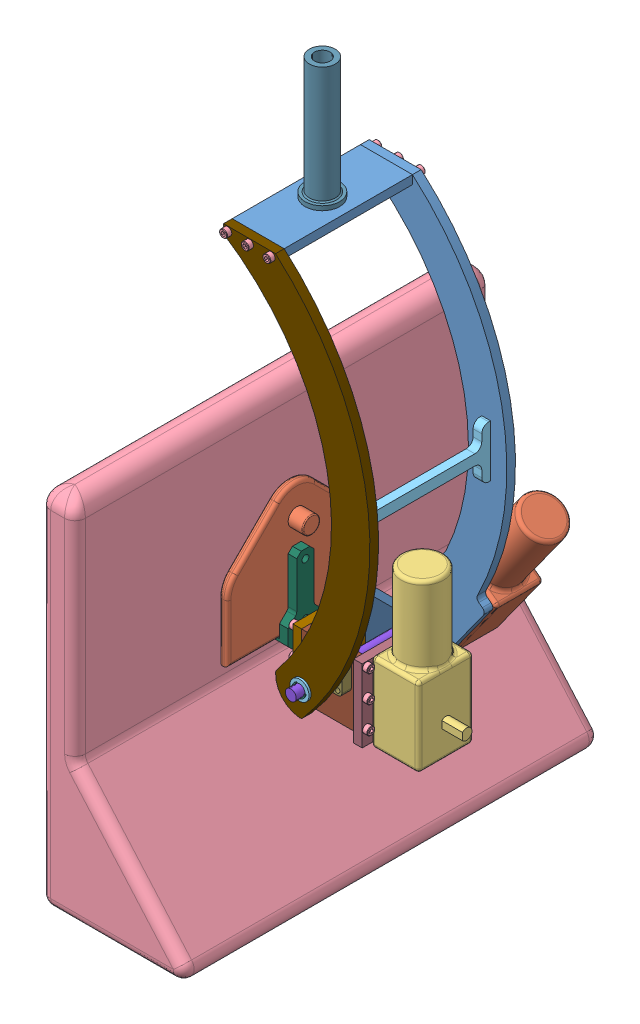
SolidWorks assembly Wrist Assembly, configuration Zero position. Lengths in mm.
Overall size (162.26 489.02 304.8).
43 component instances, 23 part files, 72 mates.
Components (placement in the parent):
- Wrist Gap (1)-1: Wrist Gap (1) [Default] at (19.05 641.296 -56.0544) x (0 0 -1) z (0 1 0)
- Screen Holder-1: Screen Holder [Default] at (-5.9436 364.1185 -55.987) x (0 0 -1) z (1 0 0)
- 8mm Bottom Shaft-1: 8mm Bottom Shaft [Default] at (59.7789 359.356 -56.0544) x (0 0 -1) z (-1 0 0)
- Tobii Screen-1: Tobii Screen [Default] at (-35.1536 247.5282 -208.387)
- 8mmBushing__5448T200_MULTIPURPOSE FLANGED SLEEVE BEARING-1: 8mmBushing__5448T200_MULTIPURPOSE FLANGED SLEEVE BEARING [5448T2] at (57.15 380.946 -1.2144) x (0.886816 0.462123 0) z (-0.462123 0.886816 0)
- 98808A340_LOW CLEARANCE EXTERNAL RETAINING RING-1: 98808A340_LOW CLEARANCE EXTERNAL RETAINING RING [98808A340] at (57.15 380.946 -0.8969) x (0 0 -1) z (0.826634 -0.56274 0)
- 5395T211_SET SCREW RIGID SHAFT COUPLING (1)-3: 5395T211_SET SCREW RIGID SHAFT COUPLING (1) [5395T211] at (57.15 380.946 -96.1006) x (0.038678 0.999252 0) z (0 0 1)
- 5395T211_SET SCREW RIGID SHAFT COUPLING (1)-4: 5395T211_SET SCREW RIGID SHAFT COUPLING (1) [5395T211] at (61.6362 359.356 -56.0544) x (0 0.396842 -0.917887) z (1 0 0)
- 8mm shaft-2: 8mm shaft [Default] at (57.15 380.946 -94.3944) x (-0.367467 -0.930037 0) z (0 0 1)
- Roll Back Plate-2: Roll Back Plate [Default] at (24.13 346.656 -29.3844) x (0 0 -1) z (1 0 0)
- Roll Right Plate RH-1: Roll Right Plate RH [Default] at (68.58 346.656 -76.3744) x (-1 0 0) z (0 0 -1)
- Roll Right Plate-2: Roll Right Plate [Default] at (68.58 346.656 -29.3844) x (-1 0 0) z (0 0 -1)
- Pitch Shaft Clamp2-1: Pitch Shaft Clamp2 [Default] at (57.15 380.946 -29.0082)
- 8mmBushing__5448T200_MULTIPURPOSE FLANGED SLEEVE BEARING-4: 8mmBushing__5448T200_MULTIPURPOSE FLANGED SLEEVE BEARING [5448T2] at (31.98 359.356 -56.0544) x (0 0.967097 -0.254408) z (0 0.254408 0.967097)
- Roll Front Plate-1: Roll Front Plate [Default] at (68.58 339.036 -29.3844) x (0 0 -1) z (1 0 0)
- WristPivotTube ACB 6804 (1)-1: WristPivotTube ACB 6804 (1) [Default] at (19.05 641.296 -56.0544) x (0 0 1) z (-1 0 0)
- roll mount-1: roll mount [Default] at (6.7564 364.1185 -106.787) x (0 0 1) z (-1 0 0)
- hex bolt_ai-1: hex bolt_ai [HBOLT 0.2500-20x0.75x0.75-N] at (19.05 634.8698 -56.0544) x (0 1 0) z (-0.999654 0 0.026315)
- flat washer type a wide_ai-1: flat washer type a wide_ai [Preferred Wide FW 0.25] at (19.05 641.296 -56.0544) x (0 1 0) z (0.546944 0 -0.837169)
- Wrist Arm Encoder Side-1: Wrist Arm Encoder Side [Default] at (19.05 380.946 -9.0644) x (0 0 1) z (-1 0 0)
- Wrist Arm Motor Side-1: Wrist Arm Motor Side [Default] at (19.05 380.946 -109.3944) x (0 0 1) z (-1 0 0)
- Single Shaft Worm Motor-1: Single Shaft Worm Motor [Default] at (77.5629 409.2685 -126.7934) x (0 0 1) z (-0.811253 0.584695 0)
- Dual Shaft Worm Motor-1: Dual Shaft Worm Motor [Default] at (92.329 394.268 -56.0544)
- socket head cap screw_ai-6: socket head cap screw_ai [HX-SHCS 0.138-32x0.5x0.5-N] at (3.175 644.471 0.7908) x (0 0 -1) z (-0.821098 0.570787 0)
- socket head cap screw_ai-7: socket head cap screw_ai [HX-SHCS 0.138-32x0.5x0.5-N] at (3.175 644.471 -112.8996) x (0 0 1) z (-0.649793 0.760112 0)
- socket head cap screw_ai-8: socket head cap screw_ai [HX-SHCS 0.138-32x0.5x0.5-N] at (78.4352 389.201 -32.5594) x (-1 0 0) z (0 0.570787 0.821098)
- socket head cap screw_ai-9: socket head cap screw_ai [HX-SHCS 0.138-32x0.5x0.5-N] at (20.6248 389.201 -79.5494) x (1 0 0) z (0 0.570787 -0.821098)
- socket head cap screw_ai-10: socket head cap screw_ai [HX-SHCS 0.138-32x0.5x0.5-N] at (78.4352 369.516 -79.5494) x (-1 0 0) z (0 0.570787 0.821098)
- socket head cap screw_ai-11: socket head cap screw_ai [HX-SHCS 0.138-32x0.5x0.5-N] at (78.4352 369.516 -32.5594) x (-1 0 0) z (0 0.570787 0.821098)
- socket head cap screw_ai-12: socket head cap screw_ai [HX-SHCS 0.138-32x0.5x0.5-N] at (78.4352 349.831 -32.5594) x (-1 0 0) z (0 0.570787 0.821098)
- socket head cap screw_ai-13: socket head cap screw_ai [HX-SHCS 0.138-32x0.5x0.5-N] at (78.4352 349.831 -79.5494) x (-1 0 0) z (0 0.570787 0.821098)
- socket head cap screw_ai-14: socket head cap screw_ai [HX-SHCS 0.138-32x0.5x0.5-N] at (78.4352 389.201 -79.5494) x (-1 0 0) z (0 0.570787 0.821098)
- socket head cap screw_ai-15: socket head cap screw_ai [HX-SHCS 0.138-32x0.5x0.5-N] at (20.6248 349.577 -32.5594) x (1 0 0) z (0 0.570787 -0.821098)
- socket head cap screw_ai-16: socket head cap screw_ai [HX-SHCS 0.138-32x0.5x0.5-N] at (20.6248 369.389 -32.5594) x (1 0 0) z (0 0.570787 -0.821098)
- socket head cap screw_ai-17: socket head cap screw_ai [HX-SHCS 0.138-32x0.5x0.5-N] at (20.6248 349.577 -79.5494) x (1 0 0) z (0 0.570787 -0.821098)
- socket head cap screw_ai-18: socket head cap screw_ai [HX-SHCS 0.138-32x0.5x0.5-N] at (20.6248 369.389 -79.5494) x (1 0 0) z (0 0.570787 -0.821098)
- socket head cap screw_ai-19: socket head cap screw_ai [HX-SHCS 0.138-32x0.5x0.5-N] at (20.6248 389.201 -32.5594) x (1 0 0) z (0 0.570787 -0.821098)
- socket head cap screw_ai-20: socket head cap screw_ai [HX-SHCS 0.138-32x0.5x0.5-N] at (34.925 644.471 0.7908) x (0 0 -1) z (-0.821098 0.570787 0)
- socket head cap screw_ai-21: socket head cap screw_ai [HX-SHCS 0.138-32x0.5x0.5-N] at (19.05 644.471 0.7908) x (0 0 -1) z (-0.821098 0.570787 0)
- socket head cap screw_ai-22: socket head cap screw_ai [HX-SHCS 0.138-32x0.5x0.5-N] at (19.05 644.471 -112.8996) x (0 0 1) z (-0.649793 0.760112 0)
- socket head cap screw_ai-23: socket head cap screw_ai [HX-SHCS 0.138-32x0.5x0.5-N] at (34.925 644.471 -112.8996) x (0 0 1) z (-0.649793 0.760112 0)
- 98808A340_LOW CLEARANCE EXTERNAL RETAINING RING-2: 98808A340_LOW CLEARANCE EXTERNAL RETAINING RING [98808A340] at (32.2975 359.356 -56.0544) x (-1 0 0) z (0 -0.153392 0.988165)
- wrist stiffner-1: wrist stiffner [Default] at (88.9 481.911 -9.0644) x (0 0 -1) z (1 0 0)
Mates (geometry in assembly coordinates):
- Parallel4: parallel anti-aligned: line of Screen Holder-1 through (-9.7536 376.8185 -94.087) axis (0 0 1); line of Tobii Screen-1 through (-9.7536 351.9913 88.793) axis (0 0 -1)
- Coincident57: coincident anti-aligned: plane of Screen Holder-1 through (-9.7536 376.8185 -55.987) normal (-1 0 0); plane of Tobii Screen-1 through (-9.7536 514.2282 96.413) normal (1 0 0)
- Width7: width anti-aligned: plane of Tobii Screen-1 through (-35.1536 247.5282 -208.387) normal (0 0 -1); plane of Tobii Screen-1 through (-35.1536 247.5282 96.413) normal (0 0 1); plane of Screen Holder-1 through (0.4064 414.9185 -5.187) normal (0 0 1); plane of Screen Holder-1 through (0.4064 364.1185 -106.787) normal (0 0 -1)
- Concentric56: concentric anti-aligned: cylinder of 8mmBushing__5448T200_MULTIPURPOSE FLANGED SLEEVE BEARING-1 through (57.15 380.946 -11.2144) axis (0 0 1) radius 4; cylinder of 8mm shaft-2 through (57.15 380.946 5.1736) axis (0 0 -1) radius 4
- Concentric58: concentric aligned: cylinder of 5395T211_SET SCREW RIGID SHAFT COUPLING (1)-3 through (57.15 380.946 -83.6006) axis (0 0 -1) radius 4; cylinder of 8mm shaft-2 through (57.15 380.946 5.1736) axis (0 0 -1) radius 4
- Concentric64: concentric aligned: cylinder of Roll Back Plate-2 through (24.13 359.356 -56.0544) axis (1 0 0) radius 5.5; cylinder of 8mmBushing__5448T200_MULTIPURPOSE FLANGED SLEEVE BEARING-4 through (21.98 359.356 -56.0544) axis (1 0 0) radius 5.525
- Concentric66: concentric aligned: cylinder of Wrist Gap (1)-1 through (19.05 647.646 -56.0544) axis (0 -1 0) radius 9.525; cylinder of WristPivotTube ACB 6804 (1)-1 through (19.05 736.546 -56.0544) axis (0 -1 0) radius 9.525
- Coincident108: coincident anti-aligned: plane of Wrist Gap (1)-1 through (12.7 647.646 -48.9548) normal (1 0 0); plane of WristPivotTube ACB 6804 (1)-1 through (12.7 665.9377 -63.6744) normal (-1 0 0)
- Coincident109: coincident aligned: plane of Wrist Gap (1)-1 through (19.05 641.296 -56.0544) normal (0 -1 0); plane of WristPivotTube ACB 6804 (1)-1 through (19.05 641.296 -56.0544) normal (0 -1 0)
- Coincident110: coincident anti-aligned: plane of Screen Holder-1 through (0.4064 364.1185 -5.187) normal (0 -1 0); plane of roll mount-1 through (-2.7686 364.1185 -68.687) normal (0 1 0)
- Coincident111: coincident anti-aligned: plane of Screen Holder-1 through (0.4064 364.1185 -55.987) normal (1 0 0); plane of roll mount-1 through (0.4064 421.2685 -68.687) normal (-1 0 0)
- Width10: width anti-aligned: plane of roll mount-1 through (-2.7686 421.2685 -43.287) normal (0 0 1); plane of roll mount-1 through (-2.7686 421.2685 -68.687) normal (0 0 -1); plane of Screen Holder-1 through (0.4064 364.1185 -106.787) normal (0 0 -1); plane of Screen Holder-1 through (0.4064 414.9185 -5.187) normal (0 0 1)
- Distance1: distance = 7.62 mm: plane of roll mount-1 through (-2.7686 354.5935 -68.687) normal (0 -1 0); line of Tobii Screen-1 through (-7.8682 346.9735 -200.767) axis (0 0 1)
- Lock1: lock: unknown of 8mm shaft-2; unknown of Pitch Shaft Clamp2-1
- Distance8: distance = 17.3736 mm anti-aligned: plane of roll mount-1 through (6.7564 364.1185 -106.787) normal (1 0 0); plane of Roll Back Plate-2 through (24.13 346.656 -29.3844) normal (-1 0 0)
- Coincident124: coincident anti-aligned: plane of 8mmBushing__5448T200_MULTIPURPOSE FLANGED SLEEVE BEARING-1 through (57.15 380.946 -1.2144) normal (0 0 1); plane of 98808A340_LOW CLEARANCE EXTERNAL RETAINING RING-1 through (59.622 380.4709 -1.2144) normal (0 0 -1)
- Concentric68: concentric aligned: cylinder of hex bolt_ai-1 through (19.05 634.8698 -56.0544) axis (0 -1 0) radius 3.175; cylinder of flat washer type a wide_ai-1 through (19.05 606.371 -56.0544) axis (0 -1 0) radius 3.9624
- Coincident125: coincident anti-aligned: plane of hex bolt_ai-1 through (18.881 639.645 -62.4753) normal (0 1 0); plane of flat washer type a wide_ai-1 through (26.8539 639.645 -50.9559) normal (0 -1 0)
- Concentric70: concentric aligned: cylinder of WristPivotTube ACB 6804 (1)-1 through (19.05 736.546 -56.0544) axis (0 -1 0) radius 3.175; cylinder of hex bolt_ai-1 through (19.05 634.8698 -56.0544) axis (0 -1 0) radius 3.175
- Coincident126: coincident anti-aligned: plane of Wrist Gap (1)-1 through (19.05 641.296 -56.0544) normal (0 -1 0); plane of flat washer type a wide_ai-1 through (22.3672 641.296 -53.8871) normal (0 1 0)
- Coincident138: coincident anti-aligned: plane of Roll Back Plate-2 through (30.48 346.656 -29.3844) normal (1 0 0); plane of 8mmBushing__5448T200_MULTIPURPOSE FLANGED SLEEVE BEARING-4 through (30.48 359.356 -56.0544) normal (-1 0 0)
- Coincident139: coincident anti-aligned: plane of Wrist Gap (1)-1 through (0 647.646 -103.0444) normal (0 0 -1); plane of Wrist Arm Motor Side-1 through (-95.25 495.246 -103.0444) normal (0 0 1)
- Coincident140: coincident aligned: plane of Wrist Gap (1)-1 through (19.05 647.646 -56.0544) normal (0 1 0); plane of Wrist Arm Motor Side-1 through (0 647.646 -103.0444) normal (0 1 0)
- Coincident141: coincident aligned: plane of Wrist Gap (1)-1 through (0 647.646 -9.0644) normal (-1 0 0); plane of Wrist Arm Motor Side-1 through (0 647.646 -103.0444) normal (-1 0 0)
- Coincident142: coincident anti-aligned: plane of Wrist Gap (1)-1 through (0 647.646 -9.0644) normal (0 0 1); plane of Wrist Arm Encoder Side-1 through (-95.25 495.246 -9.0644) normal (0 0 -1)
- Coincident143: coincident aligned: plane of Wrist Gap (1)-1 through (19.05 647.646 -56.0544) normal (0 1 0); plane of Wrist Arm Encoder Side-1 through (0 647.646 -2.7144) normal (0 1 0)
- Coincident144: coincident aligned: plane of Wrist Gap (1)-1 through (0 647.646 -9.0644) normal (-1 0 0); plane of Wrist Arm Encoder Side-1 through (0 647.646 -2.7144) normal (-1 0 0)
- Concentric72: concentric anti-aligned: cylinder of 8mmBushing__5448T200_MULTIPURPOSE FLANGED SLEEVE BEARING-1 through (57.15 380.946 -11.2144) axis (0 0 1) radius 5.525; cylinder of Wrist Arm Encoder Side-1 through (57.15 380.946 -2.7144) axis (0 0 -1) radius 5.5
- Coincident145: coincident anti-aligned: plane of 8mmBushing__5448T200_MULTIPURPOSE FLANGED SLEEVE BEARING-1 through (57.15 380.946 -2.7144) normal (0 0 -1); plane of Wrist Arm Encoder Side-1 through (-95.25 495.246 -2.7144) normal (0 0 1)
- Concentric75: concentric aligned: cylinder of 8mm shaft-2 through (57.15 380.946 5.1736) axis (0 0 -1) radius 4; cylinder of Single Shaft Worm Motor-1 through (57.15 380.946 -94.3944) axis (0 0 -1) radius 4
- Coincident147: coincident anti-aligned: plane of Wrist Arm Motor Side-1 through (-95.25 495.246 -109.3944) normal (0 0 -1); plane of Single Shaft Worm Motor-1 through (27.4234 374.0196 -109.3944) normal (0 0 1)
- Parallel24: parallel aligned: plane of Wrist Arm Motor Side-1 through (60.7234 353.3229 -103.0444) normal (0.811253 -0.584695 0); plane of Single Shaft Worm Motor-1 through (59.9806 350.5547 -144.1924) normal (0.811253 -0.584695 0)
- Coincident149: coincident anti-aligned: plane of Roll Front Plate-1 through (74.93 339.036 -29.3844) normal (1 0 0); plane of Dual Shaft Worm Motor-1 through (74.93 336.356 -35.9884) normal (-1 0 0)
- Distance9: distance = 0.7937 mm anti-aligned: plane of 5395T211_SET SCREW RIGID SHAFT COUPLING (1)-3 through (57.15 380.946 -108.6006) normal (0 0 -1); plane of Single Shaft Worm Motor-1 through (27.4234 374.0196 -109.3944) normal (0 0 1)
- Coincident152: coincident anti-aligned: plane of 8mm shaft-2 through (57.15 380.946 -94.3944) normal (0 0 -1); plane of Single Shaft Worm Motor-1 through (77.5629 409.2685 -94.3944) normal (0 0 1)
- Distance11: distance = 0.7937 mm anti-aligned: plane of 5395T211_SET SCREW RIGID SHAFT COUPLING (1)-4 through (74.1363 359.356 -56.0544) normal (1 0 0); plane of Dual Shaft Worm Motor-1 through (74.93 336.356 -35.9884) normal (-1 0 0)
- Coincident154: coincident anti-aligned: plane of Wrist Arm Encoder Side-1 through (-95.25 495.246 -2.7144) normal (0 0 1); plane of socket head cap screw_ai-6 through (1.5367 642.1143 -2.7144) normal (0 0 -1)
- Concentric80: concentric aligned: cylinder of Wrist Arm Encoder Side-1 through (3.175 644.471 -2.7144) axis (0 0 1) radius 1.8986; cylinder of socket head cap screw_ai-6 through (3.175 644.471 32.5408) axis (0 0 1) radius 1.7526
- Coincident155: coincident anti-aligned: plane of Wrist Arm Motor Side-1 through (-95.25 495.246 -109.3944) normal (0 0 -1); plane of socket head cap screw_ai-7 through (5.3567 646.336 -109.3944) normal (0 0 1)
- Concentric81: concentric anti-aligned: cylinder of Wrist Arm Motor Side-1 through (3.175 644.471 -103.0444) axis (0 0 1) radius 1.8986; cylinder of socket head cap screw_ai-7 through (3.175 644.471 -144.6496) axis (0 0 -1) radius 1.7526
- Coincident156: coincident anti-aligned: plane of Roll Back Plate-2 through (24.13 346.656 -29.3844) normal (-1 0 0); plane of socket head cap screw_ai-9 through (24.13 386.8443 -81.1876) normal (1 0 0)
- Concentric82: concentric anti-aligned: cylinder of Roll Back Plate-2 through (30.48 389.201 -79.5494) axis (1 0 0) radius 1.8986; cylinder of socket head cap screw_ai-9 through (-11.1252 389.201 -79.5494) axis (-1 0 0) radius 1.7526
- Coincident157: coincident anti-aligned: plane of Roll Front Plate-1 through (74.93 339.036 -29.3844) normal (1 0 0); plane of socket head cap screw_ai-8 through (74.93 386.8443 -30.9211) normal (-1 0 0)
- Concentric83: concentric aligned: cylinder of Roll Front Plate-1 through (74.93 389.201 -32.5594) axis (1 0 0) radius 1.8986; cylinder of socket head cap screw_ai-8 through (110.1852 389.201 -32.5594) axis (1 0 0) radius 1.7526
- Coincident159: coincident anti-aligned: plane of Wrist Gap (1)-1 through (0 647.646 -9.0644) normal (-1 0 0); plane of assembly through (0 0 0) normal (1 0 0)
- Concentric84: concentric anti-aligned: cylinder of 8mm shaft-2 through (57.15 380.946 5.1736) axis (0 0 -1) radius 4; cylinder of Pitch Shaft Clamp2-1 through (57.15 380.946 -22.0232) axis (0 0 1) radius 4
- Concentric85: concentric anti-aligned: cylinder of 98808A340_LOW CLEARANCE EXTERNAL RETAINING RING-1 through (57.15 380.946 -1.2144) axis (0 0 1) radius 4.7752; cylinder of 8mm shaft-2 through (57.15 380.946 5.1736) axis (0 0 -1) radius 4
- Coincident160: coincident anti-aligned: plane of Roll Back Plate-2 through (30.48 346.656 -29.3844) normal (1 0 0); plane of Roll Right Plate RH-1 through (30.48 346.656 -82.7244) normal (-1 0 0)
- Coincident161: coincident aligned: plane of Roll Back Plate-2 through (30.48 346.656 -82.7244) normal (0 0 -1); plane of Roll Right Plate RH-1 through (68.58 346.656 -82.7244) normal (0 0 -1)
- Coincident162: coincident aligned: plane of Roll Back Plate-2 through (30.48 392.376 -29.3844) normal (0 1 0); plane of Roll Right Plate RH-1 through (68.58 392.376 -82.7244) normal (0 1 0)
- Coincident163: coincident aligned: plane of Roll Right Plate RH-1 through (68.58 392.376 -82.7244) normal (0 1 0); plane of Roll Front Plate-1 through (74.93 392.376 -29.3844) normal (0 1 0)
- Concentric86: concentric aligned: cylinder of 8mm shaft-2 through (57.15 380.946 5.1736) axis (0 0 -1) radius 4; cylinder of Roll Right Plate RH-1 through (57.15 380.946 -76.3744) axis (0 0 -1) radius 4
- Coincident164: coincident anti-aligned: plane of Roll Back Plate-2 through (30.48 346.656 -29.3844) normal (1 0 0); plane of Roll Right Plate-2 through (30.48 346.656 -35.7344) normal (-1 0 0)
- Coincident165: coincident aligned: plane of Roll Back Plate-2 through (30.48 346.656 -29.3844) normal (0 0 1); plane of Roll Right Plate-2 through (68.58 346.656 -29.3844) normal (0 0 1)
- Coincident166: coincident aligned: plane of Roll Back Plate-2 through (30.48 392.376 -29.3844) normal (0 1 0); plane of Roll Right Plate-2 through (68.58 392.376 -35.7344) normal (0 1 0)
- Coincident167: coincident aligned: plane of Roll Right Plate-2 through (68.58 392.376 -35.7344) normal (0 1 0); plane of Roll Front Plate-1 through (74.93 392.376 -29.3844) normal (0 1 0)
- Concentric87: concentric anti-aligned: cylinder of 8mm shaft-2 through (57.15 380.946 5.1736) axis (0 0 -1) radius 4; circle of Roll Right Plate-2
- Concentric88: concentric anti-aligned: cylinder of Roll Right Plate-2 through (64.0648 387.8608 -35.7344) axis (0 0 -1) radius 1.8986; cylinder of Pitch Shaft Clamp2-1 through (64.0648 387.8608 -22.0232) axis (0 0 1) radius 1.8986
- Width11: width anti-aligned: plane of Roll Right Plate-2 through (68.58 346.656 -29.3844) normal (0 0 1); plane of Roll Right Plate RH-1 through (68.58 346.656 -82.7244) normal (0 0 -1); plane of Wrist Arm Encoder Side-1 through (-95.25 495.246 -9.0644) normal (0 0 -1); plane of Wrist Arm Motor Side-1 through (-95.25 495.246 -103.0444) normal (0 0 1)
- Concentric89: concentric aligned: cylinder of 8mm Bottom Shaft-1 through (-1.1811 359.356 -56.0544) axis (1 0 0) radius 4; cylinder of 98808A340_LOW CLEARANCE EXTERNAL RETAINING RING-2 through (31.98 359.356 -56.0544) axis (1 0 0) radius 4.7752
- Coincident170: coincident anti-aligned: plane of 8mmBushing__5448T200_MULTIPURPOSE FLANGED SLEEVE BEARING-4 through (31.98 359.356 -56.0544) normal (1 0 0); plane of 98808A340_LOW CLEARANCE EXTERNAL RETAINING RING-2 through (31.98 358.015 -53.9241) normal (-1 0 0)
- Coincident171: coincident anti-aligned: plane of Roll Right Plate-2 through (68.58 346.656 -35.7344) normal (1 0 0); plane of Roll Front Plate-1 through (68.58 339.036 -29.3844) normal (-1 0 0)
- Coincident215: coincident anti-aligned: plane of Wrist Arm Encoder Side-1 through (-95.25 495.246 -9.0644) normal (0 0 -1); plane of wrist stiffner-1 through (95.25 481.911 -9.0644) normal (0 0 1)
- Distance30: distance = 57.15 mm aligned: plane of wrist stiffner-1 through (95.25 514.931 -10.3344) normal (1 0 0); plane of Wrist Gap (1)-1 through (38.1 647.646 -9.0644) normal (1 0 0)
- Distance31: distance = 136.525 mm anti-aligned: plane of wrist stiffner-1 through (95.25 504.771 -20.4944) normal (0 1 0); plane of Wrist Gap (1)-1 through (19.05 641.296 -56.0544) normal (0 -1 0)
- Parallel25: parallel aligned: plane of Wrist Gap (1)-1 through (0 647.646 -9.0644) normal (-1 0 0); plane of Tobii Screen-1 through (-32.6136 247.5282 -208.387) normal (-1 0 0)
- Parallel26: parallel aligned: plane of Tobii Screen-1 through (-35.1536 247.5282 96.413) normal (0 0 1); plane of Wrist Arm Encoder Side-1 through (-95.25 495.246 -2.7144) normal (0 0 1)
- Concentric90: concentric aligned: cylinder of 8mm Bottom Shaft-1 through (-1.1811 359.356 -56.0544) axis (1 0 0) radius 4; cylinder of 8mmBushing__5448T200_MULTIPURPOSE FLANGED SLEEVE BEARING-4 through (21.98 359.356 -56.0544) axis (1 0 0) radius 5.525
- Concentric91: concentric anti-aligned: cylinder of 8mm Bottom Shaft-1 through (-1.1811 359.356 -56.0544) axis (1 0 0) radius 4; cylinder of 5395T211_SET SCREW RIGID SHAFT COUPLING (1)-4 through (74.1363 359.356 -56.0544) axis (-1 0 0) radius 8.5
- Concentric92: concentric aligned: cylinder of 8mm Bottom Shaft-1 through (-1.1811 359.356 -56.0544) axis (1 0 0) radius 4; cylinder of roll mount-1 through (6.7564 359.356 -56.0544) axis (1 0 0) radius 4
- Parallel27: parallel aligned: plane of 8mm Bottom Shaft-1 through (59.7789 357.7372 -56.0544) normal (0 -1 0); plane of roll mount-1 through (-2.7686 354.5935 -68.687) normal (0 -1 0)
- Distance32: distance = 1.5875 mm aligned: plane of 8mm Bottom Shaft-1 through (-1.1811 359.356 -56.0544) normal (-1 0 0); plane of roll mount-1 through (-2.7686 364.1185 -106.787) normal (-1 0 0)
